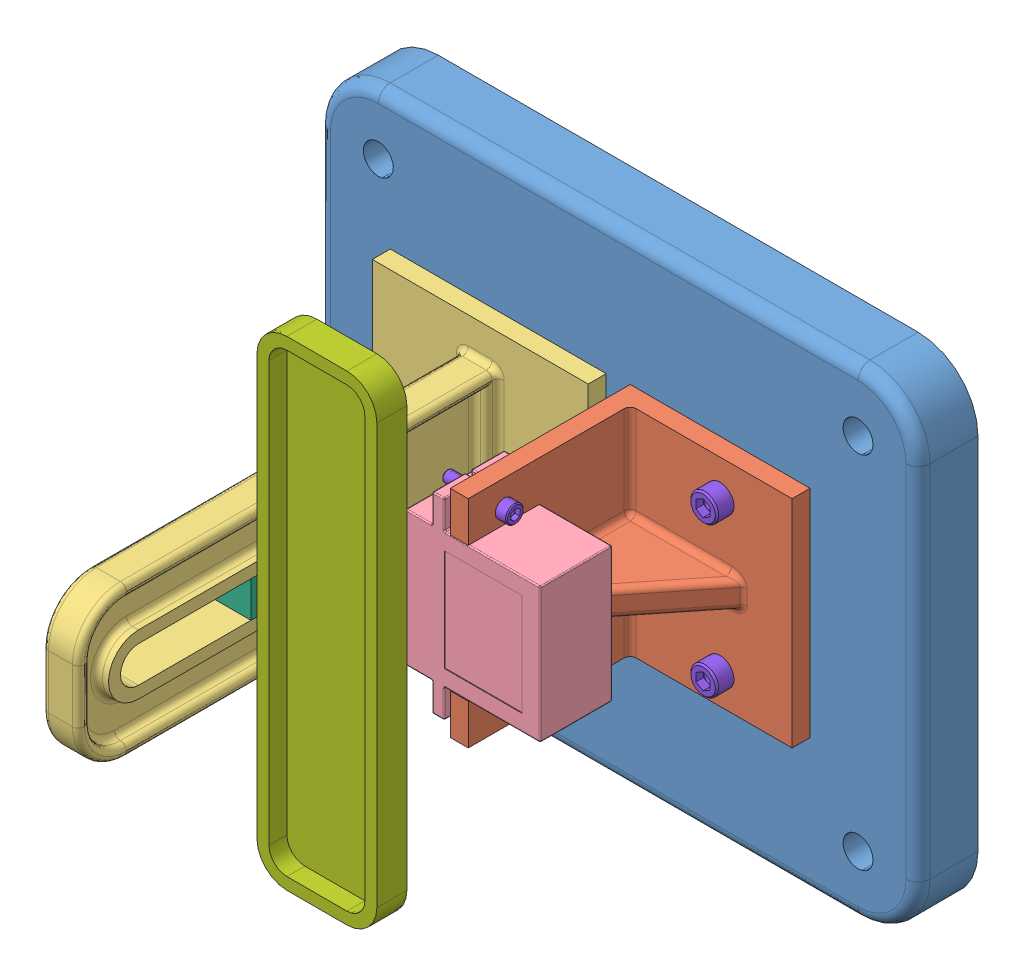
SolidWorks assembly Motion Study Assem, configuration Default. Lengths in mm.
Overall size (100 80 83).
14 component instances, 8 part files, 30 mates.
Components (placement in the parent):
- base-2: base [Default] at (5.4379 -104.5143 34.4833) size (100 80 10)
- ServoMount-1: ServoMount [Default] at (7.4379 -122.0702 44.4833) x (-1 0 0) z (0 1 0) size (30 30 36)
- bracket-1: bracket [Default] at (-14.5621 -104.5143 44.4833) size (36 36 73)
- Micro Servo FS90R Continuous-2: Micro Servo FS90R Continuous [Valor predeterminado] at (6.4379 -104.0702 68.4833) x (0 1 0) z (0 0 1) size (32 29 12)
- ServoArm-1: ServoArm [Default] at (-6.0621 -123.2801 73.9717) x (0 -0.930655 0.365897) z (1 0 0) size (38 10 4)
- clip-1: clip [Default] at (-19.5621 -104.5143 85.2222) x (0 1 0) z (1 0 0) size (10 7 8)
- Shelf-1: Shelf [Default] at (-1.5621 -104.5143 82.7222) size (26 80 5)
- socket head cap screw_ai-2: socket head cap screw_ai [HX-SHCS 0.112-40x0.375x0.375-N] at (-22.4069 -104.5143 85.2222) size (12.37 4.65 4.65)
- socket head cap screw_ai-3: socket head cap screw_ai [HX-SHCS 0.112-40x0.375x0.375-N] at (25.4379 -92.0143 50.3281) x (0 0 -1) z (1 0 0) size (12.37 4.65 4.65)
- socket head cap screw_ai-4: socket head cap screw_ai [HX-SHCS 0.112-40x0.375x0.375-N] at (25.4379 -117.0143 50.3281) x (0 0 -1) z (1 0 0) size (12.37 4.65 4.65)
- socket head cap screw_ai-5: socket head cap screw_ai [HX-SHCS 0.112-40x0.375x0.375-N] at (-24.5621 -104.5143 50.3281) x (0 0 -1) z (1 0 0) size (12.37 4.65 4.65)
- socket head cap screw_ai-6: socket head cap screw_ai [HX-SHCS 0.112-40x0.375x0.375-N] at (-4.5621 -104.5143 50.3281) x (0 0 -1) z (1 0 0) size (12.37 4.65 4.65)
- socket head cap screw_ai-8: socket head cap screw_ai [HX-SHCS 0.073-72x0.375x0.375-N] at (12.2921 -90.4452 68.4833) x (-1 0 0) z (0 0.924225 0.381849) size (11.38 3 3)
- socket head cap screw_ai-9: socket head cap screw_ai [HX-SHCS 0.073-72x0.375x0.375-N] at (12.2921 -117.6952 68.4833) x (-1 0 0) z (0 0.924225 0.381849) size (11.38 3 3)
Mates (geometry in assembly coordinates):
- Coincident1: coincident anti-aligned: plane of base-2 through (5.4379 -104.5143 44.4833) normal (0 0 1); plane of ServoMount-1 through (7.4379 -86.0702 44.4833) normal (0 0 -1)
- Concentric2: concentric aligned: cylinder of base-2 through (25.4379 -117.0143 34.4833) axis (0 0 1) radius 1.5; cylinder of ServoMount-1 through (25.4379 -117.0143 44.4833) axis (0 0 1) radius 1.5
- Concentric3: concentric aligned: cylinder of base-2 through (25.4379 -92.0143 34.4833) axis (0 0 1) radius 1.5; cylinder of ServoMount-1 through (25.4379 -92.0143 44.4833) axis (0 0 1) radius 1.5
- Coincident3: coincident anti-aligned: plane of base-2 through (5.4379 -104.5143 44.4833) normal (0 0 1); plane of bracket-1 through (-14.5621 -104.5143 44.4833) normal (0 0 -1)
- Concentric4: concentric aligned: cylinder of base-2 through (-4.5621 -104.5143 34.4833) axis (0 0 1) radius 1.5; cylinder of bracket-1 through (-4.5621 -104.5143 44.4833) axis (0 0 1) radius 1.5
- Concentric5: concentric aligned: cylinder of base-2 through (-24.5621 -104.5143 34.4833) axis (0 0 1) radius 1.5; cylinder of bracket-1 through (-24.5621 -104.5143 44.4833) axis (0 0 1) radius 1.5
- Coincident10: coincident anti-aligned: plane of ServoMount-1 through (37.4379 -92.8202 62.4833) normal (0 0 1); plane of Micro Servo FS90R Continuous-2 through (22.4379 -115.3202 62.4833) normal (0 0 -1)
- Coincident12: coincident anti-aligned: plane of ServoMount-1 through (37.4379 -115.3202 74.4833) normal (0 1 0); plane of Micro Servo FS90R Continuous-2 through (22.4379 -115.3202 62.4833) normal (0 -1 0)
- Concentric6: concentric anti-aligned: cylinder of Micro Servo FS90R Continuous-2 through (-6.5621 -109.3202 68.4833) axis (1 0 0) radius 2.25; cylinder of ServoArm-1 through (-4.0621 -109.3202 68.4833) axis (-1 0 0) radius 2.25
- Coincident13: coincident anti-aligned: plane of Micro Servo FS90R Continuous-2 through (-4.0621 -109.3202 68.4833) normal (-1 0 0); plane of ServoArm-1 through (-4.0621 -109.3202 68.4833) normal (1 0 0)
- Coincident14: coincident anti-aligned: plane of bracket-1 through (-17.5621 -117.0143 117.4833) normal (-1 0 0); plane of clip-1 through (-17.5621 -104.5143 85.2222) normal (1 0 0)
- Coincident15: coincident anti-aligned: plane of bracket-1 through (-32.5621 -107.5143 107.4833) normal (0 1 0); plane of clip-1 through (-11.5621 -107.5143 88.7222) normal (0 -1 0)
- Coincident16: coincident anti-aligned: plane of clip-1 through (-11.5621 -107.5143 87.7222) normal (0 0 -1); plane of Shelf-1 through (-1.5621 -104.5143 87.7222) normal (0 0 1)
- Coincident17: coincident anti-aligned: plane of clip-1 through (-17.5621 -104.5143 85.2222) normal (1 0 0); plane of Shelf-1 through (-17.5621 -101.5143 87.7222) normal (-1 0 0)
- Coincident18: coincident aligned: plane of clip-1 through (-11.5621 -107.5143 88.7222) normal (0 -1 0); plane of Shelf-1 through (-11.5621 -107.5143 87.7222) normal (0 -1 0)
- Distance1: distance = 1 mm anti-aligned: plane of ServoMount-1 through (7.4379 -86.0702 44.4833) normal (-1 0 0); plane of Micro Servo FS90R Continuous-2 through (6.4379 -90.4452 68.4833) normal (1 0 0)
- Concentric7: concentric anti-aligned: cylinder of clip-1 through (-19.5621 -104.5143 85.2222) axis (1 0 0) radius 1.425; cylinder of socket head cap screw_ai-2 through (-54.1569 -104.5143 85.2222) axis (-1 0 0) radius 2.3241
- Coincident19: coincident anti-aligned: plane of clip-1 through (-19.5621 -104.5143 85.2222) normal (-1 0 0); plane of socket head cap screw_ai-2 through (-19.5621 -102.1902 85.2222) normal (1 0 0)
- Concentric8: concentric aligned: cylinder of ServoMount-1 through (25.4379 -92.0143 44.4833) axis (0 0 1) radius 1.5; cylinder of socket head cap screw_ai-3 through (25.4379 -92.0143 82.0781) axis (0 0 1) radius 2.3241
- Coincident20: coincident anti-aligned: plane of ServoMount-1 through (7.4379 -86.0702 47.4833) normal (0 0 1); plane of socket head cap screw_ai-3 through (25.4379 -89.6902 47.4833) normal (0 0 -1)
- Concentric9: concentric aligned: cylinder of ServoMount-1 through (25.4379 -117.0143 44.4833) axis (0 0 1) radius 1.5; cylinder of socket head cap screw_ai-4 through (25.4379 -117.0143 82.0781) axis (0 0 1) radius 2.3241
- Coincident21: coincident anti-aligned: plane of ServoMount-1 through (7.4379 -86.0702 47.4833) normal (0 0 1); plane of socket head cap screw_ai-4 through (25.4379 -114.6902 47.4833) normal (0 0 -1)
- Concentric10: concentric aligned: cylinder of bracket-1 through (-24.5621 -104.5143 44.4833) axis (0 0 1) radius 1.5; cylinder of socket head cap screw_ai-5 through (-24.5621 -104.5143 82.0781) axis (0 0 1) radius 2.3241
- Coincident22: coincident anti-aligned: plane of bracket-1 through (-14.5621 -104.5143 47.4833) normal (0 0 1); plane of socket head cap screw_ai-5 through (-24.5621 -102.1902 47.4833) normal (0 0 -1)
- Concentric11: concentric aligned: cylinder of bracket-1 through (-4.5621 -104.5143 44.4833) axis (0 0 1) radius 1.5; cylinder of socket head cap screw_ai-6 through (-4.5621 -104.5143 82.0781) axis (0 0 1) radius 2.3241
- Coincident23: coincident anti-aligned: plane of bracket-1 through (-14.5621 -104.5143 47.4833) normal (0 0 1); plane of socket head cap screw_ai-6 through (-4.5621 -102.1902 47.4833) normal (0 0 -1)
- Concentric12: concentric anti-aligned: cylinder of ServoMount-1 through (37.4379 -90.4452 68.4833) axis (-1 0 0) radius 1; cylinder of socket head cap screw_ai-8 through (44.0421 -90.4452 68.4833) axis (1 0 0) radius 1.4986
- Coincident24: coincident anti-aligned: plane of ServoMount-1 through (10.4379 -86.0702 44.4833) normal (1 0 0); plane of socket head cap screw_ai-8 through (10.4379 -91.0175 69.8683) normal (-1 0 0)
- Concentric13: concentric anti-aligned: cylinder of ServoMount-1 through (37.4379 -117.6952 68.4833) axis (-1 0 0) radius 1; cylinder of socket head cap screw_ai-9 through (44.0421 -117.6952 68.4833) axis (1 0 0) radius 1.4986
- Coincident25: coincident anti-aligned: plane of ServoMount-1 through (10.4379 -86.0702 44.4833) normal (1 0 0); plane of socket head cap screw_ai-9 through (10.4379 -118.2675 69.8683) normal (-1 0 0)
